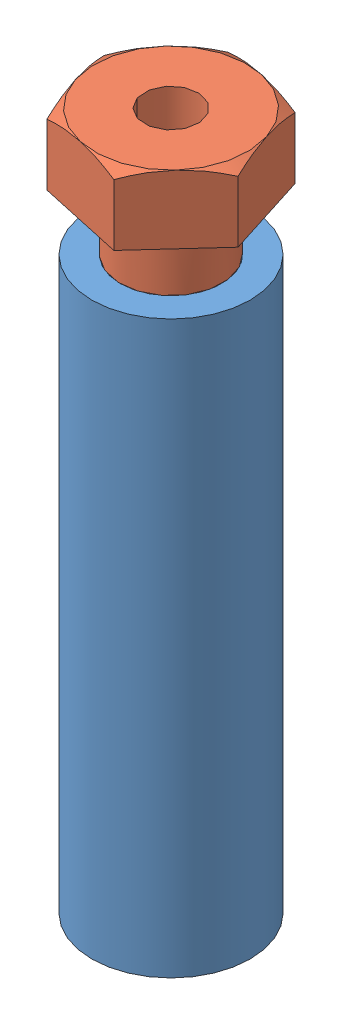
SolidWorks assembly Assem1, configuration Default. Lengths in mm.
Overall size (31.26 109.98 33.68).
2 component instances, 2 part files, 5 mates.
Components (placement in the parent):
- Body-1: Body [Default] at origin size (25 90 25)
- Screw-1: Screw [B18.2.3.5M - Hex bolt M16 x 2.0 x 65 --38S] at (0 109.9787 0) x (0 -1 0) z (-0.953085 0 0.302704) size (55.75 27.71 24)
Mates (geometry in assembly coordinates):
- Parallel1: parallel: plane of assembly through (0 0 0) normal (0 1 0); plane of Body-1 through (0 0 0) normal (0 1 0); plane of assembly
- Parallel2: parallel: plane of assembly through (0 0 0) normal (0 0 1); plane of Body-1 through (0 0 0) normal (0 0 1); plane of assembly
- Parallel3: parallel: plane of assembly through (0 0 0) normal (1 0 0); plane of Body-1 through (0 0 0) normal (1 0 0); plane of assembly
- Concentric3: concentric aligned: circle of Body-1; circle of Screw-1
- Coincident5: coincident aligned: circle of Body-1; circle of Screw-1
